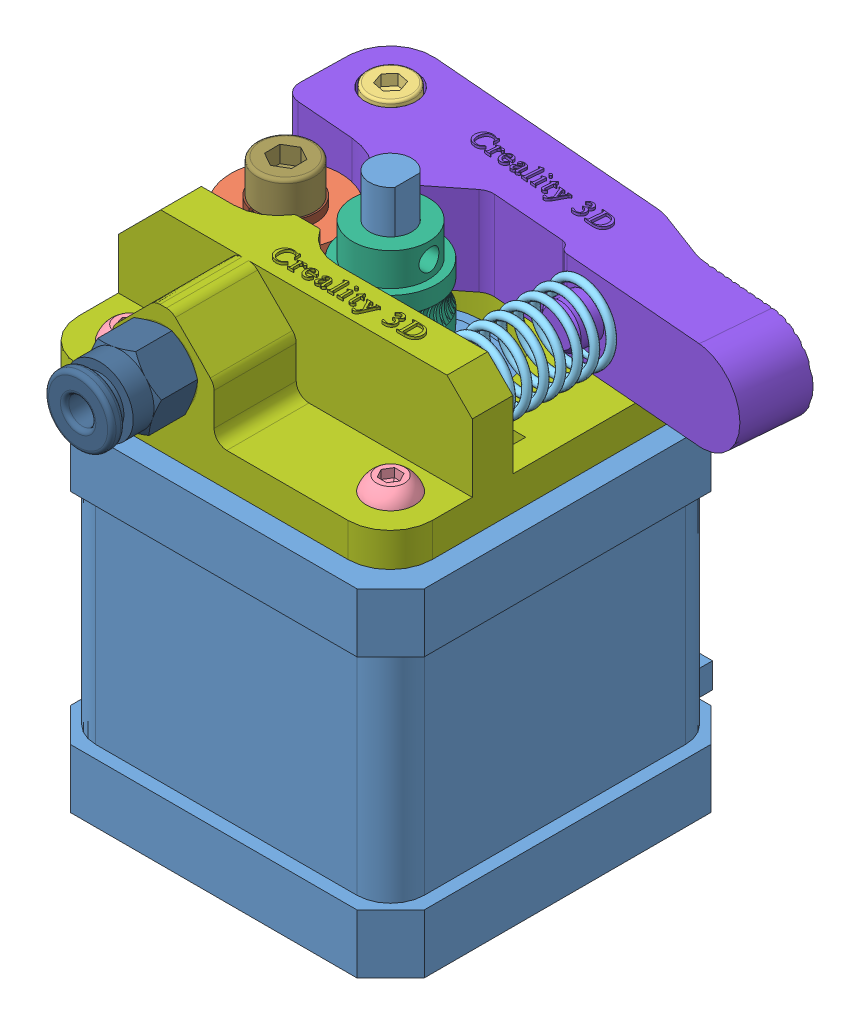
SolidWorks assembly ASM Extruder, configuration Standard. Lengths in mm.
Overall size (72.1 64 72.25).
13 component instances, 12 part files, 38 mates.
Components (placement in the parent):
- 40-42 motor-1: 40-42 motor [Standard] at origin size (42 64 50.7)
- 624U pillow-1: 624U pillow [Standard] at (17.9337 0.52 -131.5893) x (0 0 1) z (-1 0 0) size (13 4 13)
- M3X18 Socket Head Screw-1: M3X18 Socket Head Screw [Standard] at (60 56.0864 -71.9) x (0 -1 0) z (0.753538 0 0.657405) size (21 5.5 5.5)
- M3X10 Pan Head Screw-1: M3X10 Pan Head Screw [Standard] at (60 49.6964 -40.9) x (0 -1 0) z (-0.674609 0 0.738175) size (12.25 6.02 6.02)
- Extrusion Spring-1: Extrusion Spring [Standard] at (90.351 53.5739 -49.945) x (-0.996765 0.080374 0) z (0 0 -1) size (8.97 9.04 17.16)
- E gear-1: E gear [Standard] at (-2.8606 105.9729 -108.7529) x (0.998617 0 -0.052571) z (-0.052571 0 -0.998617) size (11.22 10.9 11.22)
- E housing 2-1: E housing 2 [Standard] at (118.2674 47.0731 -59.6786) x (-0.383049 0 0.923728) z (0 1 0) size (52.19 52.2 15.38)
- E idler tensioner-1: E idler tensioner [Standard] at (117.0877 47.0731 -54.9368) x (-0.456128 0 0.889914) z (0 1 0) size (42.36 54.28 10.86)
- M3X10 Flush Head Screw-1: M3X10 Flush Head Screw [Standard] at (91 48.5464 -71.9) x (0 -1 0) z (-0.538551 0 -0.842593) size (10 5.54 5.54)
- M6 Pneumatic joint-1: M6 Pneumatic joint [Standard] at (246.0139 147.0091 151.6385) x (0 0 1) z (-0.980697 -0.195531 0) size (15.42 8.01 9.24)
- M4 Split Washer-1: M4 Split Washer [Standard] at (62.3637 56.0464 -57.0893) x (-0.17437 0 0.98468) z (0.98468 0 0.17437) size (7.19 1 7.2)
- M4X8 Socket Head Screw-1: M4X8 Socket Head Screw [Standard] at (62.3637 56.0464 -57.0893) x (0 -1 0) z (-0.99993 0 0.011845) size (12 6.8 6.8)
- M3X10 Pan Head Screw-2: M3X10 Pan Head Screw [Standard] at (91 49.6964 -40.9) x (0 -1 0) z (-0.523408 0 0.852082) size (12.25 6.02 6.02)
Mates (geometry in assembly coordinates):
- Konzentrisch58: concentric anti-aligned: cylinder of 40-42 motor-1 through (75.5 65.5264 -56.4) axis (0 -1 0) radius 2.5; cylinder of E gear-1 through (75.5 49.0014 -56.4) axis (0 1 0) radius 2.5
- Deckungsgleich47: coincident anti-aligned: plane of 624U pillow-1 through (55.252 51.0464 -48.0893) normal (0 -1 0); plane of E idler tensioner-1 through (62.3637 51.0464 -57.0893) normal (0 1 0)
- Konzentrisch55: concentric aligned: cylinder of 624U pillow-1 through (62.3637 50.5464 -57.0893) axis (0 1 0) radius 2; cylinder of E idler tensioner-1 through (62.3637 48.0464 -57.0893) axis (0 1 0) radius 1.65
- Deckungsgleich48: coincident anti-aligned: plane of 624U pillow-1 through (70.2929 55.0464 -48.0893) normal (0 1 0); plane of M4 Split Washer-1 through (62.3637 55.0464 -57.0893) normal (0 -1 0)
- Konzentrisch56: concentric aligned: cylinder of 624U pillow-1 through (62.3637 50.5464 -57.0893) axis (0 1 0) radius 2; cylinder of M4 Split Washer-1 through (62.3637 55.0464 -57.0893) axis (0 1 0) radius 2.1
- Konzentrisch57: concentric aligned: cylinder of 624U pillow-1 through (62.3637 50.5464 -57.0893) axis (0 1 0) radius 2; cylinder of M4X8 Socket Head Screw-1 through (62.3637 56.988 -57.0893) axis (0 1 0) radius 2
- Deckungsgleich50: coincident anti-aligned: plane of 624U pillow-1 through (17.9337 53.0464 -131.5893) normal (0 1 0); plane of E gear-1 through (-2.8606 53.0464 -108.7529) normal (0 -1 0)
- Konzentrisch54: concentric aligned: cylinder of M3X18 Socket Head Screw-1 through (60 40.0864 -71.9) axis (0 1 0) radius 1.6; cylinder of E idler tensioner-1 through (60 47.5439 -71.9) axis (0 1 0) radius 1.608
- Deckungsgleich46: coincident anti-aligned: plane of M3X18 Socket Head Screw-1 through (61.8079 56.0864 -73.9722) normal (0 -1 0); plane of E idler tensioner-1 through (60.4496 56.0864 -77.4697) normal (0 1 0)
- Konzentrisch80: concentric aligned: cylinder of M3X18 Socket Head Screw-1 through (60 40.0864 -71.9) axis (0 1 0) radius 1.6; cylinder of E housing 2-1 through (60 44.0264 -71.9) axis (0 1 0) radius 1.7587
- Deckungsgleich52: coincident: plane of M3X10 Pan Head Screw-1 through (60 48.0464 -40.9) normal (0 -1 0); plane of E housing 2-1 through (48.4838 47.5464 -73.2775) normal (0 1 0)
- Konzentrisch60: concentric: cylinder of M3X10 Pan Head Screw-1 through (64 41.5464 -57.7) axis (0 1 0) radius 1.5; cylinder of E housing 2-1 through (64 47.5464 -57.7) axis (0 1 0) radius 1.7587
- Konzentrisch77: concentric aligned: cylinder of M3X10 Pan Head Screw-1 through (60 42.0464 -40.9) axis (0 1 0) radius 1.5; cylinder of E housing 2-1 through (60 48.0464 -40.9) axis (0 1 0) radius 1.7587
- Deckungsgleich70: coincident anti-aligned: plane of M3X10 Pan Head Screw-1 through (60 48.0464 -40.9) normal (0 -1 0); plane of E housing 2-1 through (75.5775 48.0464 -56.4162) normal (0 1 0)
- Konzentrisch59: concentric: line of Extrusion Spring-1 through (55.8386 53.0739 -88.051) axis (-1 0 0); cylinder of E housing 2-1 through (54.955 53.0739 -88.051) axis (-1 0 0) radius 2.5125
- Deckungsgleich51: coincident: plane of Extrusion Spring-1; plane of E housing 2-1 through (54.955 61.1139 -52.1725) normal (-1 0 0)
- Konzentrisch79: concentric aligned: line of Extrusion Spring-1 through (90.351 53.5739 -49.0614) axis (0 0 -1); cylinder of E housing 2-1 through (90.351 53.5739 -49.945) axis (0 0 -1) radius 2.5125
- Deckungsgleich73: coincident anti-aligned: plane of Extrusion Spring-1 through (97.5033 47.981 -49.945) normal (0 0 1); plane of E housing 2-1 through (54.4725 61.6139 -49.945) normal (0 0 -1)
- Konzentrisch48: concentric aligned: cylinder of E housing 2-1 through (69.447 53.0714 -39.3725) axis (0 0 1) radius 2.5; cylinder of M6 Pneumatic joint-1 through (69.447 53.0714 -25.3725) axis (0 0 1) radius 1.6
- Deckungsgleich42: coincident: plane of E housing 2-1 through (69.5275 43.5264 -94.3825) normal (1 0 0); plane of M6 Pneumatic joint-1 through (69.447 53.0714 -35.3725) normal (0 0 -1)
- Konzentrisch53: concentric: cylinder of E housing 2-1 through (33 43.5264 -57.7) axis (0 1 0) radius 1.7587; cylinder of E idler tensioner-1 through (33 58.0989 -57.7) axis (0 1 0) radius 3.015
- Deckungsgleich45: coincident: plane of E housing 2-1 through (48.4838 47.5464 -73.2775) normal (0 1 0); plane of E idler tensioner-1 through (50.0062 48.0464 -78.3127) normal (0 -1 0)
- Deckungsgleich53: coincident: plane of E housing 2-1 through (48.4838 47.5464 -73.2775) normal (0 1 0); plane of M3X10 Pan Head Screw-2 through (91 48.0464 -40.9) normal (0 -1 0)
- Konzentrisch61: concentric: cylinder of E housing 2-1 through (64 43.5264 -88.7) axis (0 1 0) radius 1.7587; cylinder of M3X10 Pan Head Screw-2 through (64 41.5464 -88.7) axis (0 1 0) radius 1.5
- Konzentrisch62: concentric: cylinder of E housing 2-1 through (33 43.5264 -88.7) axis (0 1 0) radius 1.7587; cylinder of M3X10 Flush Head Screw-1 through (33 38.147 -88.7) axis (0 1 0) radius 1.5293
- Tangential1: tangent: circle of E housing 2-1; cone of M3X10 Flush Head Screw-1 through (33 47.5577 -88.7) axis (0 -1 0)
- Konzentrisch78: concentric aligned: cylinder of E housing 2-1 through (91 44.0264 -40.9) axis (0 1 0) radius 1.7587; cylinder of M3X10 Pan Head Screw-2 through (91 42.0464 -40.9) axis (0 1 0) radius 1.5
- Deckungsgleich71: coincident anti-aligned: plane of E housing 2-1 through (75.5775 48.0464 -56.4162) normal (0 1 0); plane of M3X10 Pan Head Screw-2 through (91 48.0464 -40.9) normal (0 -1 0)
- Deckungsgleich72: coincident anti-aligned: plane of E housing 2-1 through (96.6825 44.0264 -35.3725) normal (0 0 1); plane of M6 Pneumatic joint-1 through (69.447 53.0714 -35.3725) normal (0 0 -1)
- Deckungsgleich74: coincident anti-aligned: plane of E housing 2-1 through (75.5775 48.0464 -56.4162) normal (0 1 0); plane of E idler tensioner-1 through (50.0062 48.0464 -78.3127) normal (0 -1 0)
- Abstand1: distance = 0.5 mm aligned: plane of M3X10 Flush Head Screw-1 through (91 48.5464 -71.9) normal (0 1 0); plane of E housing 2-1 through (75.5775 48.0464 -56.4162) normal (0 1 0)
- Deckungsgleich49: coincident anti-aligned: plane of M4 Split Washer-1 through (62.3637 56.0464 -57.0893) normal (0 1 0); plane of M4X8 Socket Head Screw-1 through (62.404 56.0464 -53.6895) normal (0 -1 0)
- Abstand2: distance = 2.5 mm anti-aligned: plane of E housing 2-1 through (75.5775 44.0264 -56.4162) normal (0 -1 0); plane of 40-42 motor-1 through (75.5 41.5264 -56.4) normal (0 1 0)
- Deckungsgleich75: coincident aligned: plane of 40-42 motor-1 through (0 0 0) normal (0 0 1); plane of assembly through (0 0 0) normal (0 0 1)
- Deckungsgleich76: coincident aligned: plane of 40-42 motor-1 through (0 0 0) normal (0 1 0); plane of assembly through (0 0 0) normal (0 1 0)
- Deckungsgleich77: coincident aligned: plane of 40-42 motor-1 through (0 0 0) normal (1 0 0); plane of assembly through (0 0 0) normal (1 0 0)
- Konzentrisch81: concentric aligned: cylinder of 40-42 motor-1 through (91 36.5264 -40.9) axis (0 1 0) radius 1.5; cylinder of M3X10 Pan Head Screw-2 through (91 42.0464 -40.9) axis (0 1 0) radius 1.5
- Konzentrisch82: concentric aligned: cylinder of 40-42 motor-1 through (60 36.5264 -71.9) axis (0 1 0) radius 1.5; cylinder of M3X18 Socket Head Screw-1 through (60 40.0864 -71.9) axis (0 1 0) radius 1.6
